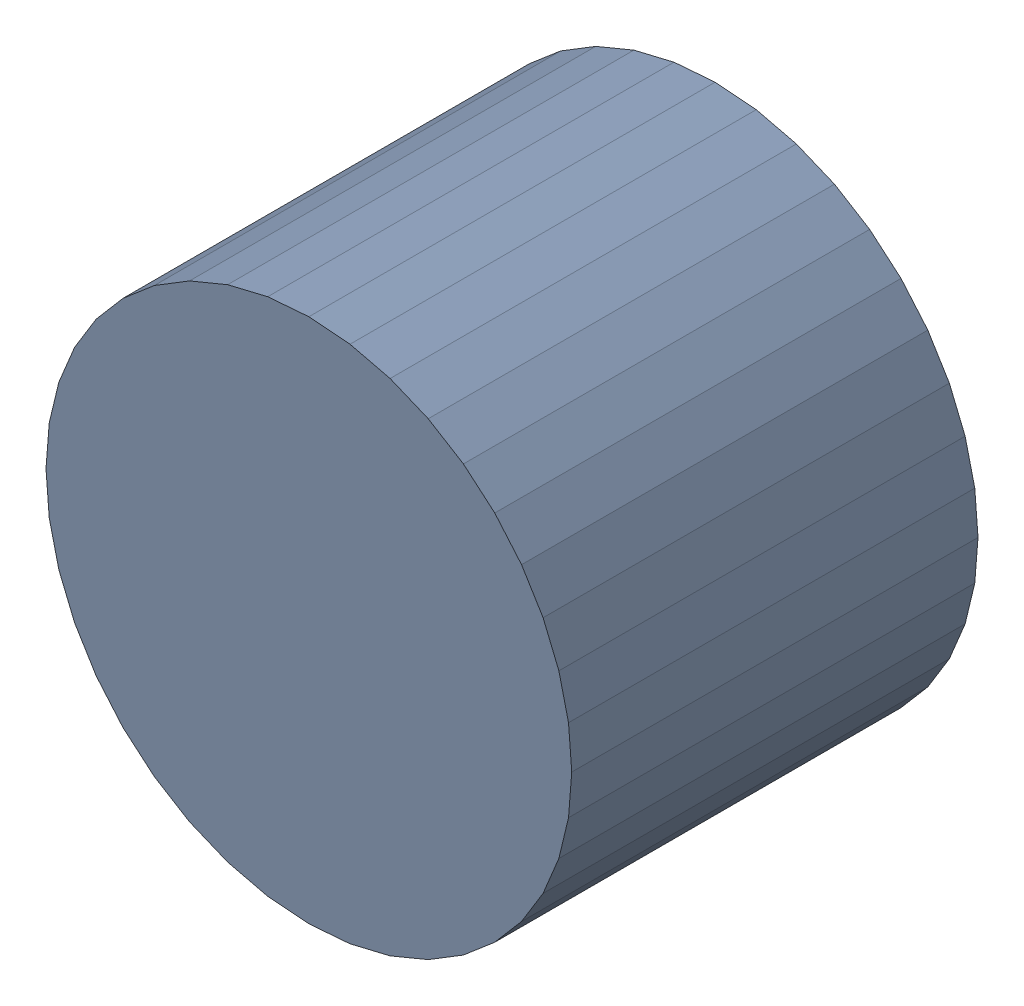
SolidWorks assembly C20Kanaloa_v2.0.0_Power, configuration Default. Lengths in mm.
Overall size (8.02 8.02 6.2).
2 component instances, 1 part files, 0 mates.
Components (placement in the parent):
- 425994496-1: 425994496 [Default] at (102.591 160.68 0) size (8.02 8.02 6.2)
  - Extruded_22-1: Extruded_22 [Default] at origin size (8.02 8.02 6.2)
